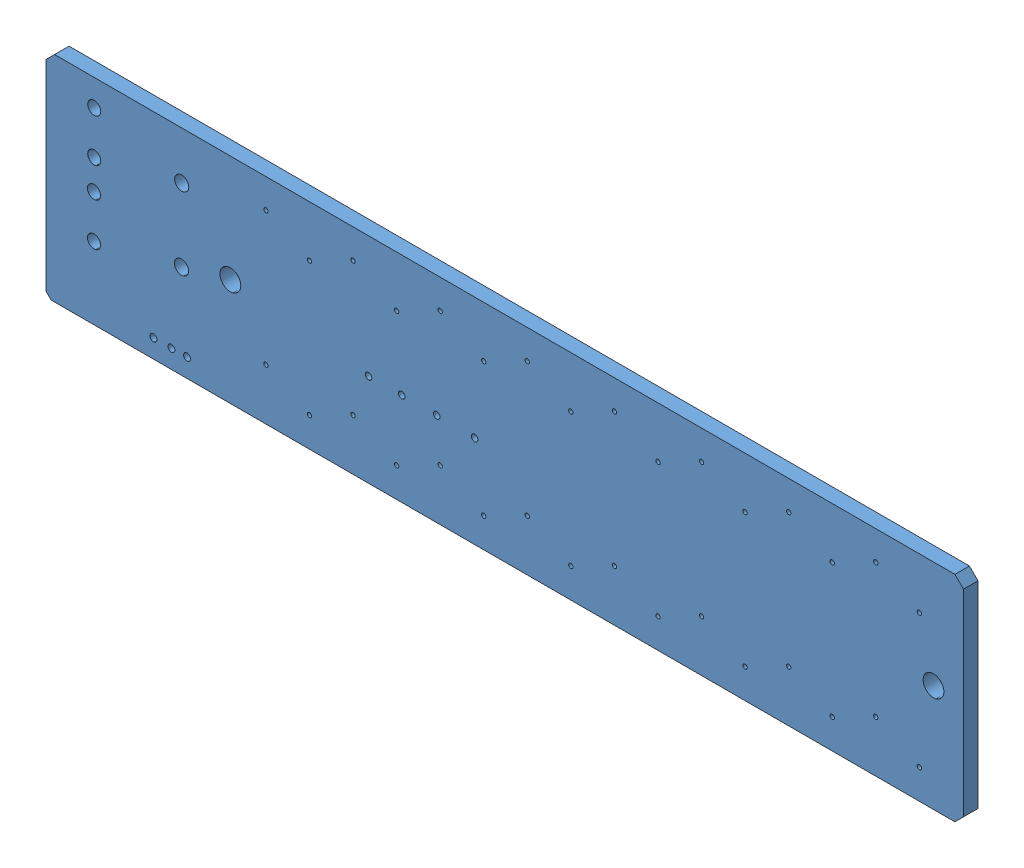
SolidWorks assembly pigtail_v2_revc, configuration Default. Lengths in mm.
Overall size (107 25 1.69).
23 component instances, 8 part files, 0 mates.
Components (placement in the parent):
- Board_2-1: Board_2 [Default] at (0 0 -1.6916) size (107 25 1.69)
- J3_1-1: J3_1 [Default] at origin size (19.05 7.9 7.4) (hidden)
  - Jack_PCB_1-1: Jack_PCB_1 [Default] at (7.9749 19.4619 4) x (-1 0 0) z (0 1 0) size (19.05 7.4 7.9)
- J4_1-1: J4_1 [Default] at origin size (19.05 7.9 7.4) (hidden)
  - Jack_PCB_1-1: Jack_PCB_1 [Default] at (7.9499 10.9619 4) x (-1 0 0) z (0 1 0) size (19.05 7.4 7.9)
- J1_1-1: J1_1 [Default] at origin size (86.5 7.28 11.56) (hidden)
  - mill-max-0908-2-15-20-75-14-11-0_2-1: mill-max-0908-2-15-20-75-14-11-0_2 [Default] at (102.9839 2.6516 1.27) x (0 0 1) z (1 0 0) size (3.33 1.01 1.01)
    - mill-max-0908-2-15-20-75-14-11-0_SPRING_1-1: mill-max-0908-2-15-20-75-14-11-0_SPRING_1 [Default] at (5.5978 -0.8235 -1.1087) x (0 -0.998082 0.061903) z (-1 0 0) size (0.96 0.96 3.33)
  - mill-max-0908-2-15-20-75-14-11-0_3-1: mill-max-0908-2-15-20-75-14-11-0_3 [Default] at (102.9839 2.6516 1.27) x (0 0 1) z (1 0 0) size (9.22 1.83 1.83)
    - mill-max-0908-2-15-20-75-14-11-0_0963-0_0963-0-00-20-00-00-13-0_1-1: mill-max-0908-2-15-20-75-14-11-0_0963-0_0963-0-00-20-00-00-13-0_1 [Default] at (0.1795 -0.8235 -1.1087) size (4.04 1.31 1.31)
    - mill-max-0908-2-15-20-75-14-11-0_0954-0_0954-0-00-20-00-00-13-0_1-1: mill-max-0908-2-15-20-75-14-11-0_0954-0_0954-0-00-20-00-00-13-0_1 [Default] at (1.9321 -0.8235 -1.1087) size (5.03 1.83 1.83)
    - mill-max-0908-2-15-20-75-14-11-0_SPRING_0975-0-00-00-75-14-45-0_1-1: mill-max-0908-2-15-20-75-14-11-0_SPRING_0975-0-00-00-75-14-45-0_1 [Default] at (5.5978 -0.8235 -1.1087) x (0 -0.998082 0.061903) z (-1 0 0) size (0.8 0.8 3.43)
    - mill-max-0908-2-15-20-75-14-11-0_0918-X_0918-7-00-20-00-00-13-0_1-1: mill-max-0908-2-15-20-75-14-11-0_0918-X_0918-7-00-20-00-00-13-0_1 [Default] at (3.9133 -0.8235 -1.1087) x (1 0 0) z (0 0.540629 0.841261) size (5.49 1.25 1.25)
  - wire_connector_1-1: wire_connector_1 [Default] at (18.525 4.6649 3.4087) x (1 0 0) z (0 -1 0) size (86.5 9.6 7.28)
- J2_1-1: J2_1 [Default] at origin size (86.5 7.28 11.56) (hidden)
  - mill-max-0908-2-15-20-75-14-11-0_2-1: mill-max-0908-2-15-20-75-14-11-0_2 [Default] at (102.9839 18.2516 1.27) x (0 0 1) z (1 0 0) size (3.33 1.01 1.01)
    - mill-max-0908-2-15-20-75-14-11-0_SPRING_1-1: mill-max-0908-2-15-20-75-14-11-0_SPRING_1 [Default] at (5.5978 -0.8235 -1.1087) x (0 -0.998082 0.061903) z (-1 0 0) size (0.96 0.96 3.33)
  - mill-max-0908-2-15-20-75-14-11-0_3-1: mill-max-0908-2-15-20-75-14-11-0_3 [Default] at (102.9839 18.2516 1.27) x (0 0 1) z (1 0 0) size (9.22 1.83 1.83)
    - mill-max-0908-2-15-20-75-14-11-0_0963-0_0963-0-00-20-00-00-13-0_1-1: mill-max-0908-2-15-20-75-14-11-0_0963-0_0963-0-00-20-00-00-13-0_1 [Default] at (0.1795 -0.8235 -1.1087) size (4.04 1.31 1.31)
    - mill-max-0908-2-15-20-75-14-11-0_0954-0_0954-0-00-20-00-00-13-0_1-1: mill-max-0908-2-15-20-75-14-11-0_0954-0_0954-0-00-20-00-00-13-0_1 [Default] at (1.9321 -0.8235 -1.1087) size (5.03 1.83 1.83)
    - mill-max-0908-2-15-20-75-14-11-0_SPRING_0975-0-00-00-75-14-45-0_1-1: mill-max-0908-2-15-20-75-14-11-0_SPRING_0975-0-00-00-75-14-45-0_1 [Default] at (5.5978 -0.8235 -1.1087) x (0 -0.998082 0.061903) z (-1 0 0) size (0.8 0.8 3.43)
    - mill-max-0908-2-15-20-75-14-11-0_0918-X_0918-7-00-20-00-00-13-0_1-1: mill-max-0908-2-15-20-75-14-11-0_0918-X_0918-7-00-20-00-00-13-0_1 [Default] at (3.9133 -0.8235 -1.1087) x (1 0 0) z (0 0.540629 0.841261) size (5.49 1.25 1.25)
  - wire_connector_1-1: wire_connector_1 [Default] at (18.525 20.2649 3.4087) x (1 0 0) z (0 -1 0) size (86.5 9.6 7.28)
